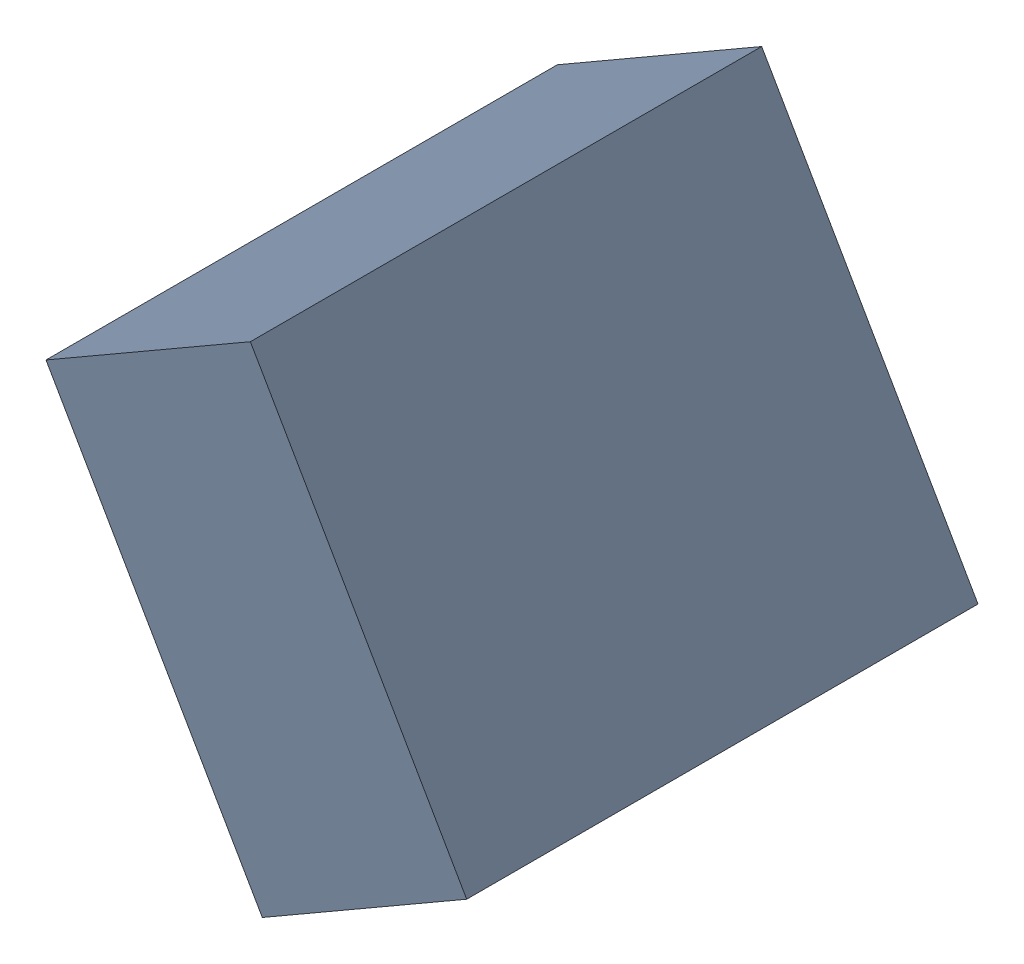
SolidWorks assembly C26_TDA2, configuration Standard. Lengths in mm.
Overall size (1.07 1.25 1.3).
2 component instances, 1 part files, 0 mates.
Components (placement in the parent):
- 885543192-1: 885543192 [Standard] at (33.0724 22.5121 0) size (1.07 1.25 1.3)
  - Extruded_27-1: Extruded_27 [Standard] at origin size (1.07 1.25 1.3)
